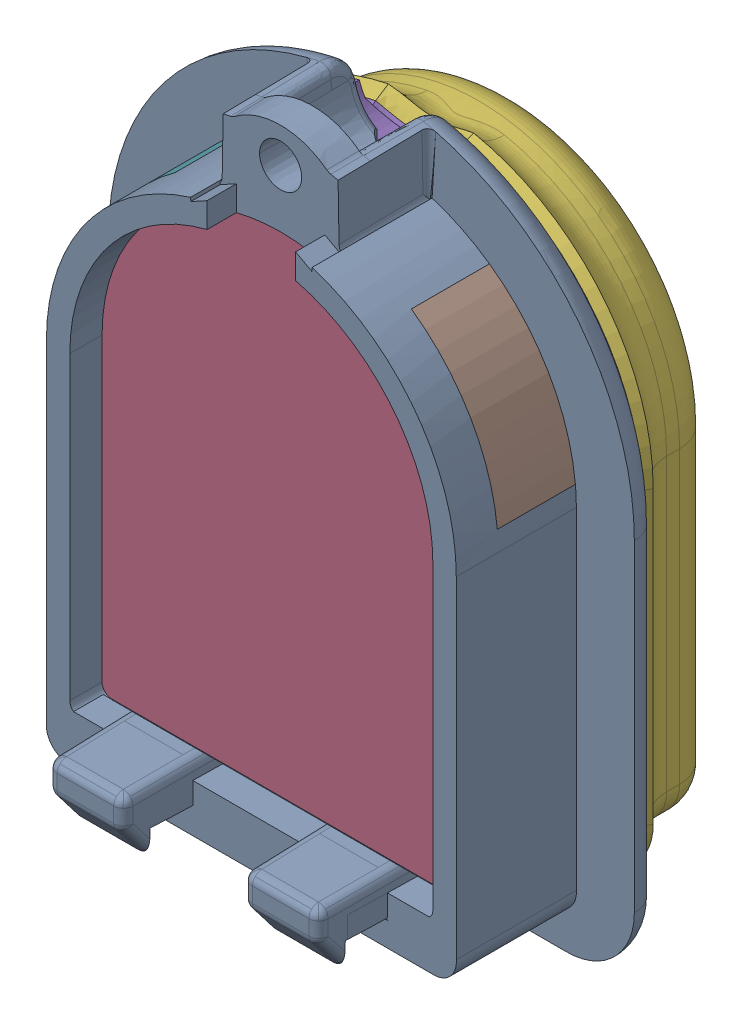
SolidWorks assembly Dot1Design, configuration 默认. Lengths in mm.
Overall size (26.95 34.26 16.36).
8 component instances, 7 part files, 22 mates.
Components (placement in the parent):
- Dot1Tip1-1: Dot1Tip1 [默认] at (-1.9035 7.7463 -5.5591) size (26.95 34.26 11.2)
- Dot1lensnew-1: Dot1lensnew [默认] at (-1.9035 7.7463 -5.5591) size (18.6 25.2 6)
- Dot1Skin0.2-1: Dot1Skin0.2 [默认] at (-1.9035 7.4963 -5.5591) x (-1 0 0) z (0 0 -1) size (23.9 30.06 5.2)
- Dot1Skin1-1: Dot1Skin1 [默认] at (-1.9035 7.4963 -5.5591) x (-1 0 0) z (0 0 -1) size (22.77 29.32 5.25) (hidden)
- Dot1sidelens1-1: Dot1sidelens1 [默认] at (-1.9035 7.7463 -6.2091) size (6.4 7.71 4)
- Dot1sidelens1-2: Dot1sidelens1 [默认] at (-1.9035 7.7463 2.0909) x (-1 0 0) z (0 0 -1) size (6.4 7.71 4)
- Dot1bottomlens-1: Dot1bottomlens [默认] at (-5.9035 -10.5037 0.4409) x (1 0 0) z (0 1 0) size (8 4.5 2.35)
- Dot1DotMarker-1: Dot1DotMarker [默认] at (-7.9035 -5.4997 -10.2091) size (13 22 1)
Mates (geometry in assembly coordinates):
- 同心1: concentric aligned: cylinder of Tip1-1 through (-1.9035 7.7463 51.2878) axis (0 0 -1) radius 9.3; cylinder of lensnew-1 through (-1.9035 7.7463 0.4409) axis (0 0 -1) radius 9.3
- 重合1: coincident anti-aligned: plane of Tip1-1 through (-1.9035 -8.1537 51.2878) normal (0 1 0); plane of lensnew-1 through (-11.2035 -8.1537 0.4409) normal (0 -1 0)
- 重合2: coincident aligned: plane of Tip1-1 through (-1.964 4.3089 -5.5591) normal (0 0 -1); plane of lensnew-1 through (-1.9035 7.7463 -5.5591) normal (0 0 -1)
- 重合3: coincident anti-aligned: plane of lensnew-1 through (-1.9035 7.7463 -5.5591) normal (0 0 -1); plane of Skin0.2-1 through (-1.9035 7.4963 -5.5591) normal (0 0 1)
- 同心2: concentric aligned: cone of Tip1-1 through (-1.9035 19.9963 -1.0591) axis (0 0 1); cylinder of Skin0.2-1 through (-1.9035 19.9963 -6.3091) axis (0 0 1) radius 2.75
- 宽度1: width aligned: plane of Skin0.2-1 through (-13.8535 7.4963 -5.5591) normal (-1 0 0); plane of Skin0.2-1 through (10.0465 7.4963 -5.5591) normal (1 0 0); plane of Tip1-1 through (-12.4035 7.7463 2.0909) normal (-1 0 0); plane of Tip1-1 through (8.5965 7.7463 2.0909) normal (1 0 0)
- 重合4: coincident anti-aligned: plane of Skin0.2-1 through (-1.9035 7.4963 -10.7591) normal (0 0 -1); plane of Skin1-1 through (-1.9035 7.4963 -10.7591) normal (0 0 1)
- 宽度2: width anti-aligned: plane of Skin0.2-1 through (-13.8535 7.4963 -5.5591) normal (-1 0 0); plane of Skin0.2-1 through (10.0465 7.4963 -5.5591) normal (1 0 0); plane of Skin1-1 through (-12.8325 0.0508 -6.2245) normal (-0.891007 0 0.45399); plane of Skin1-1 through (9.0255 0.0508 -6.2245) normal (0.891007 0 0.45399)
- 重合5: coincident aligned: cone of Skin0.2-1 through (-1.9035 7.4963 -6.2245) axis (0 0 1); cone of Skin1-1 through (-1.9035 7.4963 -6.2245) axis (0 0 1)
- 重合6: coincident anti-aligned: plane of Tip1-1 through (-16.7251 9.2061 -4.0591) normal (0.104528 0.994522 0); plane of sidelens1-1 through (8.4147 6.5638 -0.0591) normal (-0.104528 -0.994522 0)
- 重合7: coincident anti-aligned: plane of Tip1-1 through (-1.9035 7.7463 -4.0591) normal (0 0 1); plane of sidelens1-1 through (8.4147 6.5638 -4.0591) normal (0 0 -1)
- 同心3: concentric aligned: cylinder of Tip1-1 through (-1.9035 7.7463 2.0909) axis (0 0 -1) radius 10.5; cylinder of sidelens1-1 through (-1.9035 7.7463 -0.0591) axis (0 0 -1) radius 10.5
- 同心4: concentric anti-aligned: cylinder of Tip1-1 through (-1.9035 7.7463 2.0909) axis (0 0 -1) radius 10.5; cylinder of sidelens1-2 through (-1.9035 7.7463 -4.0591) axis (0 0 1) radius 10.5
- 重合8: coincident anti-aligned: plane of Tip1-1 through (12.0819 17.1622 -0.0591) normal (0.104528 -0.994522 0); plane of sidelens1-2 through (-13.0579 14.5199 -4.0591) normal (-0.104528 0.994522 0)
- 重合9: coincident anti-aligned: plane of Tip1-1 through (-1.9035 7.7463 -4.0591) normal (0 0 1); plane of sidelens1-2 through (-1.9035 7.7463 -4.0591) normal (0 0 -1)
- 重合10: coincident anti-aligned: plane of lensnew-1 through (-11.2035 -8.1537 0.4409) normal (0 -1 0); plane of bottomlens-1 through (-5.9035 -8.1537 0.4409) normal (0 1 0)
- 重合11: coincident anti-aligned: plane of Tip1-1 through (-5.9035 -18.1537 0.4409) normal (0 0 -1); plane of bottomlens-1 through (-5.9035 -8.1537 0.4409) normal (0 0 1)
- 重合12: coincident anti-aligned: plane of Tip1-1 through (2.0965 -18.1537 0.4409) normal (-1 0 0); plane of bottomlens-1 through (2.0965 -8.1537 0.4409) normal (1 0 0)
- 平行1: parallel anti-aligned: plane of lensnew-1 through (-1.9035 7.7463 -5.5591) normal (0 0 -1); plane of DotMarker-1 through (-7.9035 -5.4997 -10.2091) normal (0 0 1)
- 对称1: symmetric aligned: plane of Tip1-1 through (8.5965 7.7463 2.0909) normal (1 0 0); plane of DotMarker-1 through (-12.4035 7.7463 2.0909) normal (-1 0 0); plane of Tip1-1 through (-1.9035 -5.4997 -10.2091) normal (1 0 0)
- 距离1: distance = 14 mm anti-aligned: plane of DotMarker-1 through (-7.9035 3.5003 -10.2091) normal (0 1 0); plane of Tip1-1 through (-1.9035 -10.4997 2.0909) normal (0 -1 0)
- 距离2: distance = 0.55 mm anti-aligned: plane of DotMarker-1 through (-7.9035 -5.4997 -10.2091) normal (0 0 1); plane of Skin0.2-1 through (-1.9035 7.4963 -10.7591) normal (0 0 -1)
